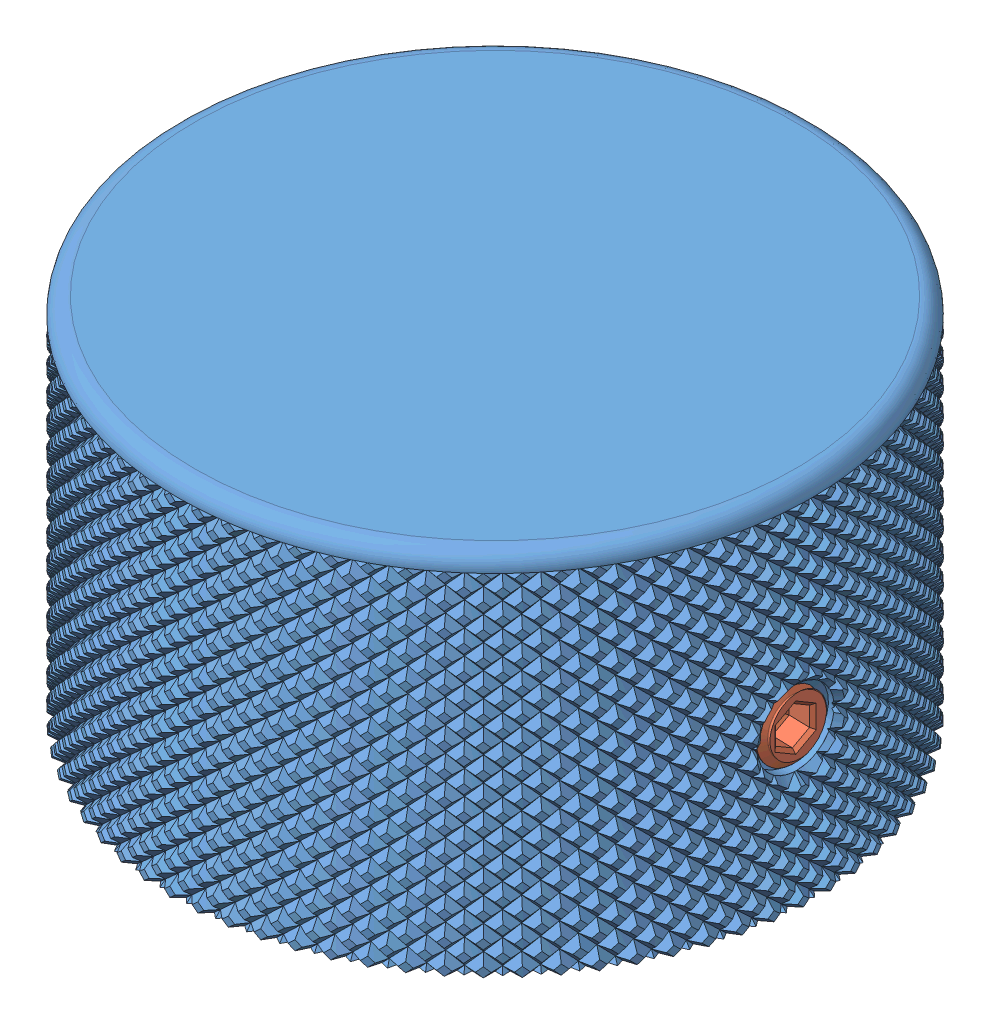
SolidWorks assembly Assem2, configuration Default. Lengths in mm.
Overall size (38.01 22.01 38.01).
2 component instances, 2 part files, 2 mates.
Components (placement in the parent):
- KNOB-1: KNOB [ﾃﾞﾌｫﾙﾄ] at (-52.6562 -5.7659 -0.0002) size (38.01 22.01 38.01)
- Hex Socket Set Screw Cup M4x10-2: Hex Socket Set Screw Cup M4x10 [Default] at (-51.1566 3.2822 0.038) x (0 -1 0) z (-0.025464 0 0.999676) size (4.63 17.63 4.13)
Mates (geometry in assembly coordinates):
- Concentric1: concentric anti-aligned: cylinder of KNOB-1 through (-33.6623 3.2822 0.4837) axis (0.999676 0 0.025464) radius 2.25; cylinder of Hex Socket Set Screw Cup M4x10-2 through (-34.1622 3.2822 0.4709) axis (-0.999676 0 -0.025464) radius 2
- Tangent1: tangent: plane of Hex Socket Set Screw Cup M4x10-2 through (-34.1622 3.2822 0.4709) normal (0.999676 0 0.025464); circle of KNOB-1
